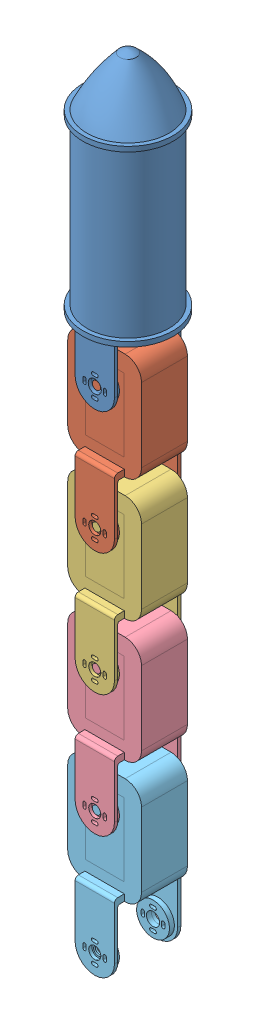
SolidWorks assembly test4_2, configuration 預設. Lengths in mm.
Overall size (55 478.78 55).
5 component instances, 5 part files, 19 mates.
Components (placement in the parent):
- base_link2-2: base_link2 [預設] at origin size (55 179.98 55)
- link1-1: link1 [預設] at (0 -157.7 0) x (0 1 0) z (0 0 -1) size (107 45 40.5)
- link2-1: link2 [預設] at (0 -232.4 0) x (0 1 0) z (0 0 -1) size (107 45 40.5)
- link3-2: link3 [預設] at (0 -307.1 0) x (0 1 0) z (0 0 -1) size (107 45 40.5)
- link4-1: link4 [預設] at (0 -381.8 0) x (0 1 0) z (0 0 -1) size (107 45 40.5)
Mates (geometry in assembly coordinates):
- 平行相距4: distance = 18.5 mm: plane of base_link2-2 through (0 -83 -18.5) normal (0 0 1); plane of assembly through (0 0 0) normal (0 0 1)
- 平行相距5: distance = 12 mm: plane of assembly through (0 0 0) normal (1 0 0); plane of base_link2-2 through (12 -53 18) normal (1 0 0)
- 平行相距6: distance = 50 mm: plane of assembly through (0 0 0) normal (0 1 0); plane of base_link2-2 through (0 -50 -0.25) normal (0 1 0)
- 同軸心2: concentric: cylinder of base_link2-2 through (0 -83 18) axis (0 0 1) radius 4; cylinder of link1-1 through (0 -83 14) axis (0 0 1) radius 2.5
- 同軸心3: concentric: cylinder of base_link2-2 through (0 -83 -20.5) axis (0 0 1) radius 4; cylinder of link1-1 through (0 -83 -19) axis (0 0 1) radius 2.5
- 平行1: parallel: plane of base_link2-2 through (12 -53 -20.5) normal (1 0 0); plane of link1-1 through (22.5 -127.7 -14) normal (1 0 0)
- 重合/共線/共點8: coincident: plane of base_link2-2 through (0 -83 -18.5) normal (0 0 1); plane of link1-1 through (0 -157.7 -18.5) normal (0 0 1)
- 同軸心4: concentric: cylinder of link1-1 through (0 -157.7 20) axis (0 0 -1) radius 3.7; cylinder of ? through (122.3295 -185.6512 7.75) axis (0 0 -1) radius 2.5
- 重合/共線/共點9: coincident: plane of link1-1 through (22.5 -127.7 -14) normal (1 0 0); plane of ?
- 重合/共線/共點10: coincident: plane of link1-1 through (0 -67.7653 20) normal (0 0 1); plane of ?
- 重合/共線/共點11: coincident: plane of link1-1 through (22.5 -127.7 -14) normal (1 0 0); plane of link2-1 through (22.5 -202.4 -14) normal (1 0 0)
- 同軸心5: concentric: cylinder of link1-1 through (0 -157.7 20) axis (0 0 -1) radius 3.7; cylinder of link2-1 through (0 -157.7 14) axis (0 0 1) radius 2.5
- 重合/共線/共點12: coincident: plane of link1-1 through (0 -67.7653 14) normal (0 0 1); plane of link2-1 through (0 -142.4653 14) normal (0 0 1)
- 重合/共線/共點14: coincident: plane of link2-1 through (22.5 -202.4 -14) normal (1 0 0); plane of link3-2 through (22.5 -277.1 -14) normal (1 0 0)
- 同軸心6: concentric: cylinder of link2-1 through (0 -232.4 -18.5) axis (0 0 -1) radius 4; cylinder of link3-2 through (0 -232.4 -19) axis (0 0 1) radius 2.5
- 重合/共線/共點15: coincident: plane of link2-1 through (0 -142.4653 -14) normal (0 0 -1); plane of link3-2 through (0 -217.1653 -14) normal (0 0 -1)
- 同軸心7: concentric: cylinder of link3-2 through (0 -307.1 20) axis (0 0 -1) radius 3.7; cylinder of link4-1 through (0 -307.1 14) axis (0 0 1) radius 2.5
- 重合/共線/共點16: coincident: plane of link3-2 through (22.5 -277.1 -14) normal (1 0 0); plane of link4-1 through (22.5 -351.8 -14) normal (1 0 0)
- 重合/共線/共點17: coincident: plane of link3-2 through (0 -217.1653 14) normal (0 0 1); plane of link4-1 through (0 -291.8653 14) normal (0 0 1)
